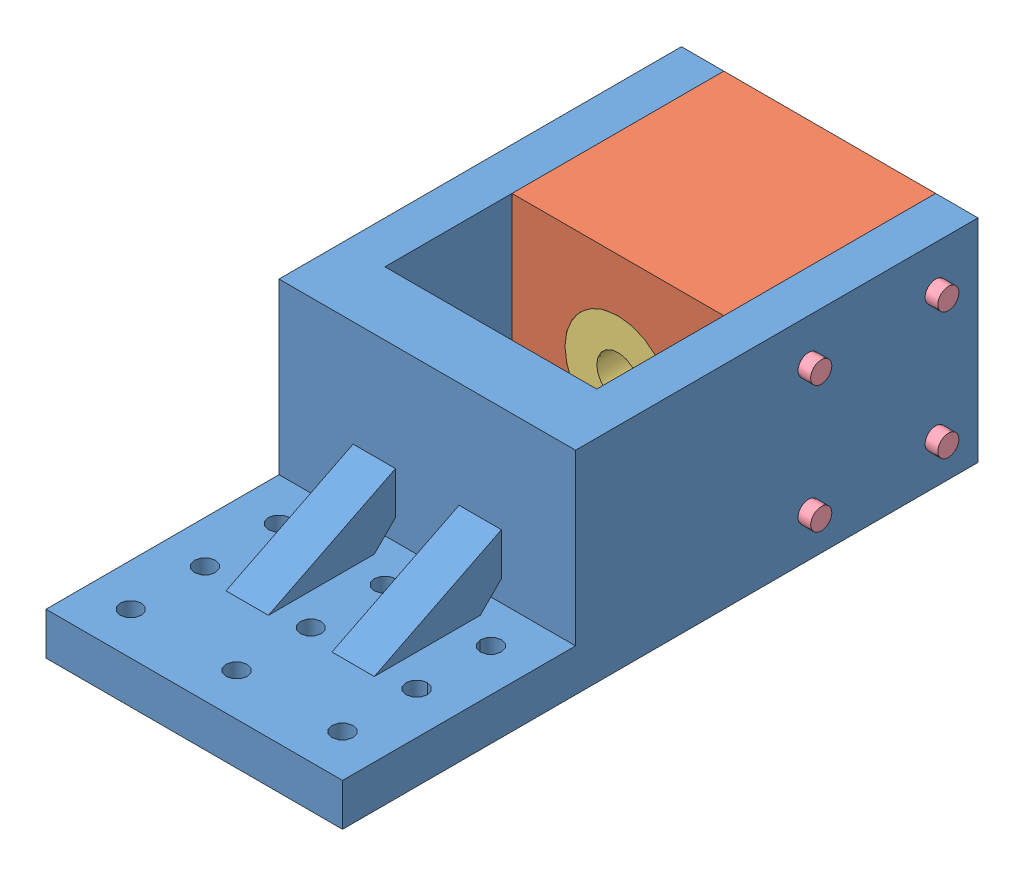
SolidWorks assembly hinten-halter, configuration Standard. Lengths in mm.
Overall size (76 50 150).
12 component instances, 4 part files, 22 mates.
Components (placement in the parent):
- halter-hinten-1: halter-hinten [Standard] at (18.3626 -24.2013 0) size (70 50 150)
- hinten-wuerfel-1: hinten-wuerfel [Standard] at (5.5256 13.6144 -80.9471) x (0 0 -1) z (1 0 0) size (50 50 50)
- lager-1: lager [Standard] at (25.9628 -25.0929 -88.4471) size (25 25 7.5)
- lager-2: lager [Standard] at (25.9628 -25.0929 -130.9471) size (25 25 7.5)
- 10_M3_imbus-1: 10_M3_imbus [Standard] at (23.802 -21.0998 -86.3482) x (0 -1 0) z (0 0 1) size (5 13 5)
- 10_M3_imbus-2: 10_M3_imbus [Standard] at (23.802 8.9002 -116.3482) x (0 -1 0) z (0 0 1) size (5 13 5)
- 10_M3_imbus-3: 10_M3_imbus [Standard] at (23.802 8.9002 -86.3482) x (0 -1 0) z (0 0 1) size (5 13 5)
- 10_M3_imbus-4: 10_M3_imbus [Standard] at (23.802 -21.0998 -116.3482) x (0 -1 0) z (0 0 1) size (5 13 5)
- 10_M3_imbus-5: 10_M3_imbus [Standard] at (-26.198 -7.3029 -86.3482) x (0 1 0) z (0 0 1) size (5 13 5)
- 10_M3_imbus-6: 10_M3_imbus [Standard] at (-26.198 22.6971 -86.3482) x (0 1 0) z (0 0 1) size (5 13 5)
- 10_M3_imbus-7: 10_M3_imbus [Standard] at (-26.198 -7.3029 -116.3482) x (0 1 0) z (0 0 1) size (5 13 5)
- 10_M3_imbus-8: 10_M3_imbus [Standard] at (-26.198 22.6971 -116.3482) x (0 1 0) z (0 0 1) size (5 13 5)
Mates (geometry in assembly coordinates):
- Deckungsgleich1: coincident aligned: axis of halter-hinten-1; axis of hinten-wuerfel-1
- Deckungsgleich2: coincident aligned: axis of halter-hinten-1; axis of hinten-wuerfel-1
- Deckungsgleich3: coincident anti-aligned: plane of halter-hinten-1 through (23.802 -24.2013 -130.9471) normal (-1 0 0); plane of hinten-wuerfel-1 through (23.802 25.7987 -130.9471) normal (1 0 0)
- Konzentrisch1: concentric aligned: circle of hinten-wuerfel-1 centre (-1.198 0.7987 -123.4471) axis (0 0 -1); cylinder of lager-2
- Deckungsgleich4: coincident anti-aligned: plane of hinten-wuerfel-1 through (-1.198 0.7987 -123.4471) normal (0 0 -1); plane of lager-2 through (-1.198 0.7987 -123.4471) normal (0 0 1)
- Deckungsgleich5: coincident aligned: circle of hinten-wuerfel-1 centre (-1.198 0.7987 -88.4471) axis (0 0 1); circle of lager-1 centre (-1.198 0.7987 -88.4471) axis (0 0 1)
- Konzentrisch2: concentric aligned: circle of halter-hinten-1; circle of 10_M3_imbus-3
- Konzentrisch3: concentric aligned: circle of 10_M3_imbus-1; circle of halter-hinten-1
- Konzentrisch4: concentric aligned: circle of halter-hinten-1; circle of 10_M3_imbus-2
- Konzentrisch5: concentric aligned: circle of halter-hinten-1; circle of 10_M3_imbus-4
- Konzentrisch6: concentric anti-aligned: circle of halter-hinten-1; circle of 10_M3_imbus-7
- Konzentrisch7: concentric anti-aligned: circle of halter-hinten-1; circle of 10_M3_imbus-5
- Konzentrisch8: concentric anti-aligned: circle of halter-hinten-1; circle of 10_M3_imbus-6
- Konzentrisch9: concentric anti-aligned: circle of halter-hinten-1; circle of 10_M3_imbus-8
- Deckungsgleich6: coincident anti-aligned: plane of halter-hinten-1; plane of 10_M3_imbus-1
- Deckungsgleich7: coincident anti-aligned: plane of halter-hinten-1; plane of 10_M3_imbus-3
- Deckungsgleich8: coincident anti-aligned: plane of halter-hinten-1; plane of 10_M3_imbus-4
- Deckungsgleich9: coincident anti-aligned: plane of halter-hinten-1; plane of 10_M3_imbus-2
- Deckungsgleich10: coincident anti-aligned: plane of halter-hinten-1; plane of 10_M3_imbus-7
- Deckungsgleich11: coincident anti-aligned: plane of halter-hinten-1; plane of 10_M3_imbus-8
- Deckungsgleich12: coincident anti-aligned: plane of halter-hinten-1; plane of 10_M3_imbus-6
- Deckungsgleich13: coincident anti-aligned: plane of halter-hinten-1; plane of 10_M3_imbus-5
